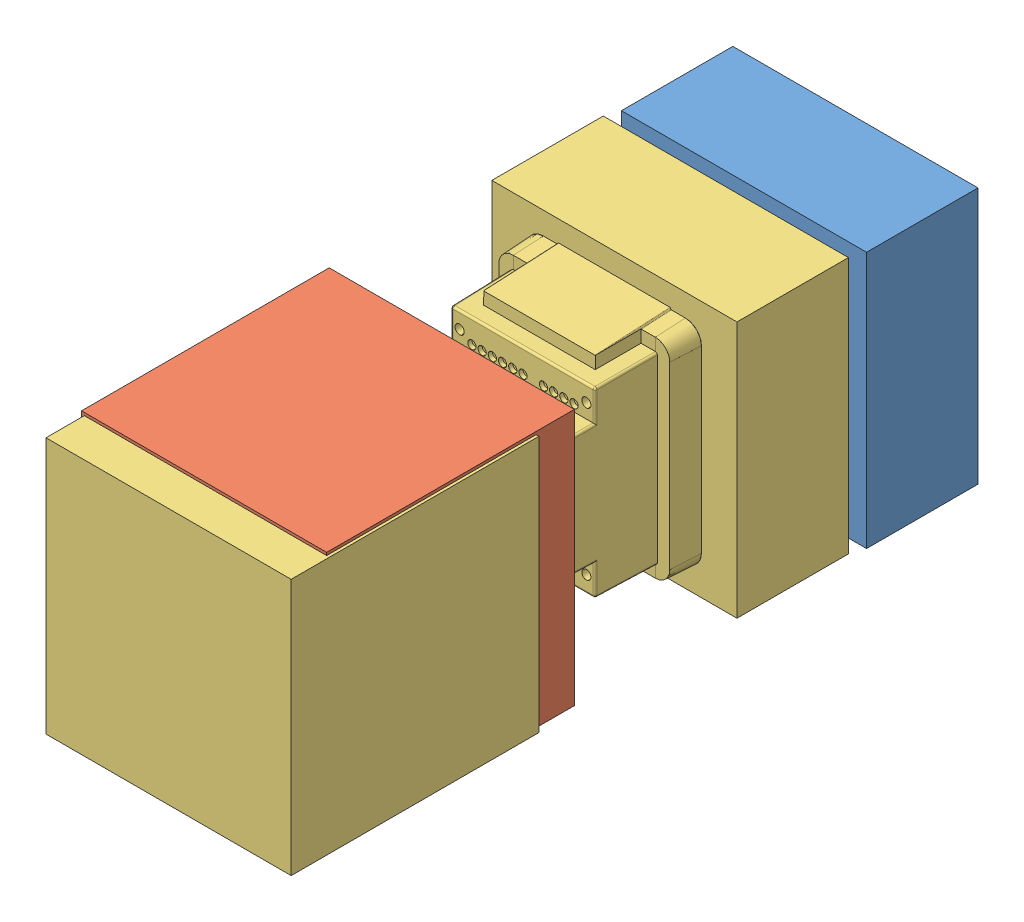
SolidWorks assembly Assem1, configuration Default. Lengths in mm.
Overall size (202.02 211.28 521.89).
4 component instances, 4 part files, 4 mates.
Components (placement in the parent):
- plc-core-1: plc-core [Default] at (34.7995 4.5318 -197.006) size (197.98 207.23 210)
- Part4^Assem1-1: Part4^Assem1 [Default] at origin (virtual)
- plc-cavity-1: plc-cavity [Default] at (30.7518 8.5795 -125.1134) size (197.98 207.23 200.05)
- Part2-2: Part2 [Default] at (33.0045 6.3268 -94.171) size (197.98 207.23 450)
Mates (geometry in assembly coordinates):
- Coincident8: coincident anti-aligned: plane of plc-cavity-1 through (-64.1407 21.3862 13.8122) normal (0 0.999848 -0.017452); plane of Part2-2 through (-61.8879 19.1335 -115.2454) normal (0 -0.999848 0.017452)
- Coincident9: coincident anti-aligned: plane of plc-cavity-1 through (53.8343 127.8112 13.8122) normal (-0.999848 0 -0.017452); plane of Part2-2 through (56.0871 125.5585 -115.2454) normal (0.999848 0 0.017452)
- Coincident20: coincident anti-aligned: plane of plc-core-1 through (-60.093 3.313 -218.138) normal (0 -0.999848 0.017452); plane of Part2-2 through (-61.8879 5.108 -115.303) normal (0 0.999848 -0.017452)
- Coincident21: coincident anti-aligned: plane of plc-core-1 through (54.5825 123.7635 -218.138) normal (0.999848 0 0.017452); plane of Part2-2 through (52.7876 125.5585 -115.303) normal (-0.999848 0 -0.017452)
